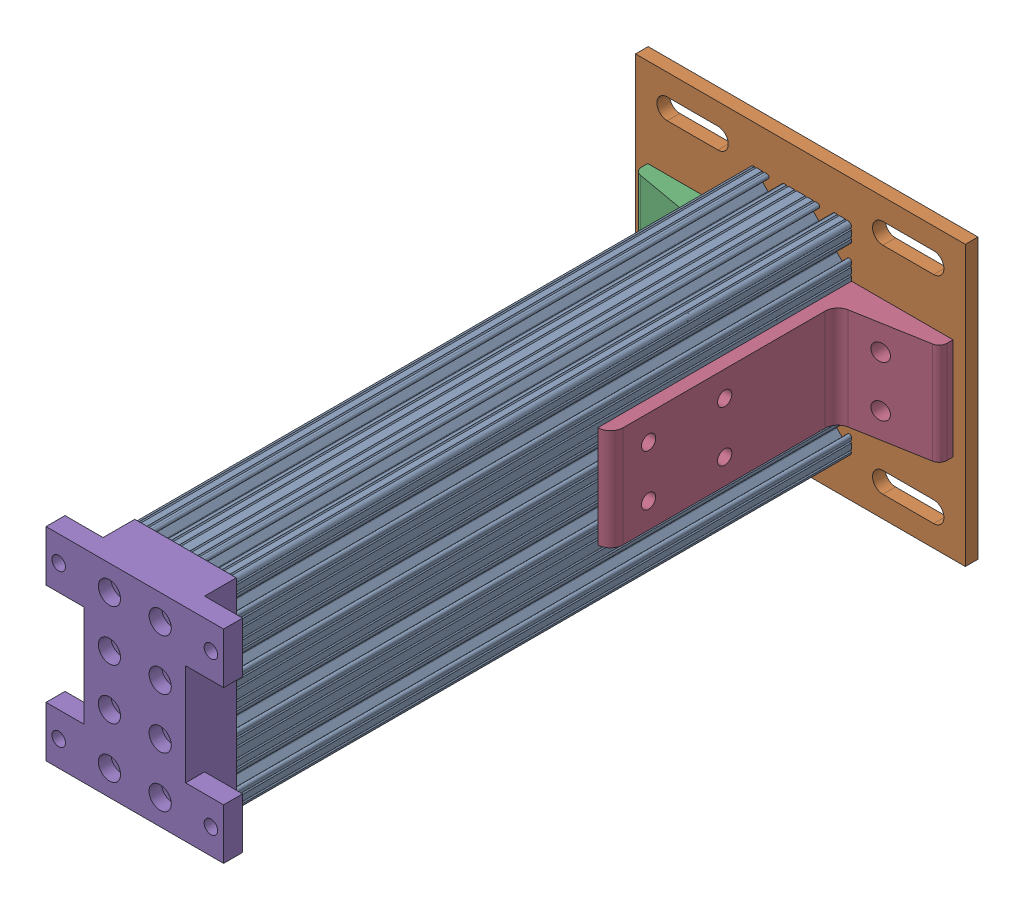
SolidWorks assembly Mirrorbreadboard support leg assembly1, configuration Default. Lengths in mm.
Overall size (165.1 139.7 339.72).
6 component instances, 4 part files, 6 mates.
Components (placement in the parent):
- Mirror8020-2040 leg for breadboard support-1: Mirror8020-2040 leg for breadboard support [Default] at (-48.9055 -77.0614 -78.1612) size (50.8 101.6 307.98)
- Mirror8020-2387-DEFAULT1-1: Mirror8020-2387-DEFAULT1 [Default] at (-34.9863 -22.6888 -91.8816) x (0 1 0) z (1 0 0) size (139.7 133.35 165.1)
  - Mirror8020-2387-DEFAULT_238708-1: Mirror8020-2387-DEFAULT_238708 [Default] at (-67.1549 7.3704 -27.8119) size (139.7 6.35 165.1)
  - Mirror8020-2387-DEFAULT_238509-1: Mirror8020-2387-DEFAULT_238509 [Default] at (9.1264 0.0214 -49.7635) x (0 0 -1) z (1 0 0) size (50.8 127 50.8)
  - Mirror8020-2387-DEFAULT_238509-2: Mirror8020-2387-DEFAULT_238509 [Default] at (-41.6736 0.0214 46.9187) x (0 0 1) z (-1 0 0) size (50.8 127 50.8)
- Mirrorbreadboard support leg top bracket-1: Mirrorbreadboard support leg top bracket [Default] at (-61.6055 -89.7614 229.8138) x (0 1 0) z (1 0 0) size (101.6 25.4 88.9)
Mates (geometry in assembly coordinates):
- Coincident1: coincident anti-aligned: plane of Mirror8020-2040 leg for breadboard support-1 through (-61.6055 -36.3198 -78.1612) normal (0 0 -1); plane of Mirror8020-2387-DEFAULT1-1/Mirror8020-2387-DEFAULT_238708-1 through (-36.4088 -207.3239 -78.1612) normal (0 0 1)
- Coincident2: coincident anti-aligned: plane of Mirror8020-2040 leg for breadboard support-1 through (-10.8056 -41.095 229.8138) normal (1 0 0); plane of Mirror8020-2387-DEFAULT1-1/Mirror8020-2387-DEFAULT_238509-2 through (-10.8056 -13.5624 -150.9329) normal (-1 0 0)
- Distance1: distance = 19.05 mm aligned: plane of Mirror8020-2387-DEFAULT1-1/Mirror8020-2387-DEFAULT_238708-1 through (-36.4088 -108.8114 -78.1612) normal (0 -1 0); plane of Mirror8020-2040 leg for breadboard support-1 through (-38.3391 -89.7614 229.8138) normal (0 -1 0)
- Coincident3: coincident anti-aligned: plane of Mirror8020-2040 leg for breadboard support-1 through (-61.6055 -36.3198 229.8138) normal (0 0 1); plane of Mirrorbreadboard support leg top bracket-1 through (-10.8055 -89.7614 229.8138) normal (0 0 -1)
- Concentric1: concentric anti-aligned: circle of Mirror8020-2040 leg for breadboard support-1; circle of Mirrorbreadboard support leg top bracket-1
- Concentric2: concentric anti-aligned: circle of Mirror8020-2040 leg for breadboard support-1; circle of Mirrorbreadboard support leg top bracket-1
